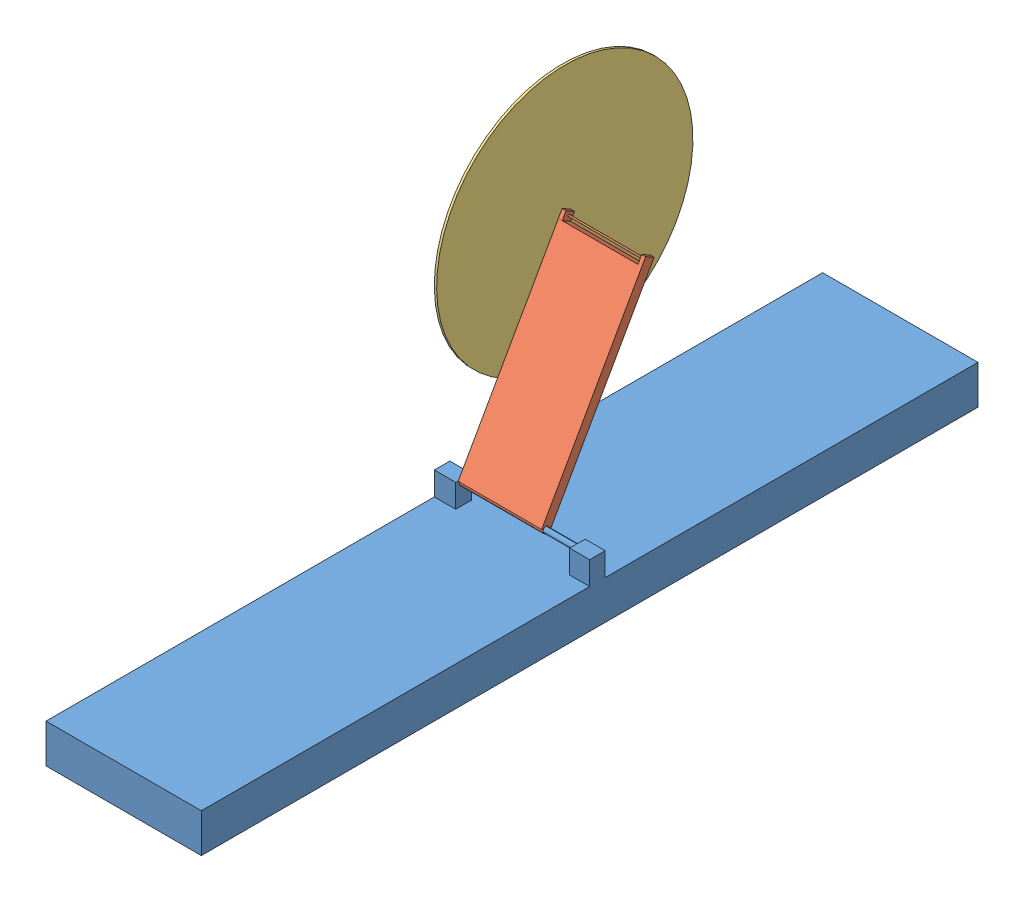
SolidWorks assembly assemblage2, configuration Défaut. Lengths in mm.
Overall size (221.45 517.57 1000).
3 component instances, 3 part files, 4 mates.
Components (placement in the parent):
- bati-1: bati [Défaut] at (-24.2088 -49.4465 1450) size (200 80 1000)
- Pièce1-1: Pièce1 [Défaut] at (-96.6597 129.9519 926.9196) x (1 0 0) z (0 0.491426 0.870919) size (156.5 276.5 12.55)
- Pièce2-1: Pièce2 [Défaut] at (-99.6597 249.205 859.5953) x (1 0 0) z (0 0.952191 -0.305502) size (3 330 330)
Mates (geometry in assembly coordinates):
- Coaxiale1: concentric aligned: cylinder of bati-1 through (-111.6597 15.7054 991.3845) axis (1 0 0) radius 3.4481; axis of Pièce1-1 through (-96.6597 15.7054 991.3845) axis (1 0 0)
- Coaxiale2: concentric aligned: cylinder of Pièce1-1 through (-145.6597 249.205 859.5953) axis (1 0 0) radius 1; cylinder of Pièce2-1 through (-106.6597 249.205 859.5953) axis (1 0 0) radius 1.2
- Coïncidente2: coincident anti-aligned: plane of Pièce1-1 through (-96.6597 129.9519 926.9196) normal (-1 0 0); plane of Pièce2-1 through (-96.6597 249.205 859.5953) normal (1 0 0)
- Coïncidente4: coincident anti-aligned: plane of bati-1 through (-96.6597 19.1535 1450) normal (1 0 0); plane of Pièce1-1 through (-96.6597 129.9519 926.9196) normal (-1 0 0)
